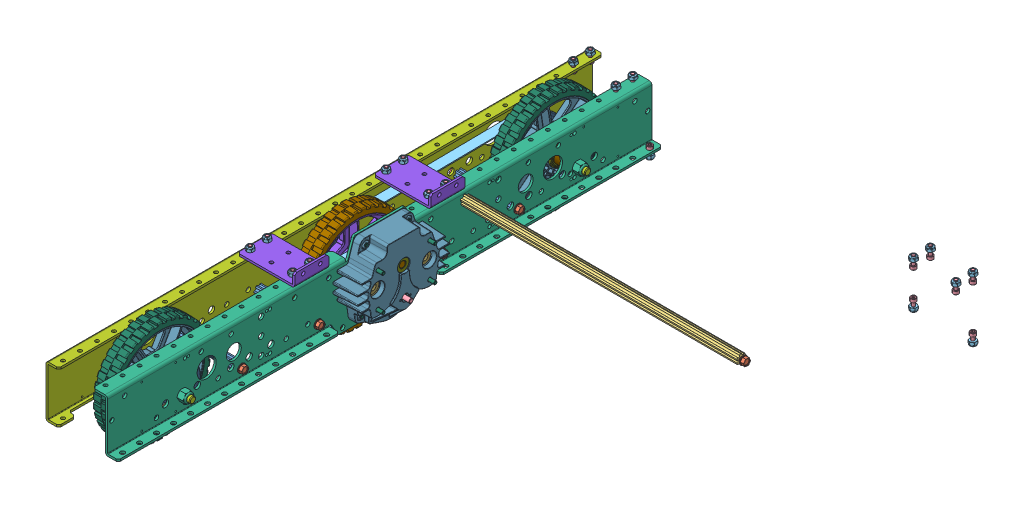
SolidWorks assembly AM14U3Long_Half, configuration Default. Lengths in mm.
Overall size (596.72 219.18 816.74).
153 component instances, 36 part files, 6 mates.
Components (placement in the parent):
- AM14U3Long_Frame_Half-1: AM14U3Long_Frame_Half [Default] at (0 136.144 -762.762) size (595.34 116.33 812.8)
  - 500Churro_3.375-1: 500Churro_3.375 [Default] at (-501.65 -66.929 448.437) x (0 0 1) z (-1 0 0) size (14.66 12.7 85.72)
  - 500Churro_3.375-2: 500Churro_3.375 [Default] at (-501.65 -66.929 562.737) x (0 0 1) z (-1 0 0) size (14.66 12.7 85.72)
  - 500Churro_3.375-3: 500Churro_3.375 [Default] at (-501.65 -66.929 264.287) x (0 0 1) z (-1 0 0) size (14.66 12.7 85.72)
  - 500Churro_3.375-4: 500Churro_3.375 [Default] at (-501.65 -66.929 149.987) x (0 0 1) z (-1 0 0) size (14.66 12.7 85.72)
  - ThreadRollingScrew_0.25-20x0.75_FHTS 0.25-20-G-0.75-C-1: ThreadRollingScrew_0.25-20x0.75_FHTS 0.25-20-G-0.75-C [Default] at (-498.475 -66.929 562.737) x (-1 0 0) z (0 0.924225 0.381849) size (24.64 12.19 12.19)
  - ThreadRollingScrew_0.25-20x0.75_FHTS 0.25-20-G-0.75-C-2: ThreadRollingScrew_0.25-20x0.75_FHTS 0.25-20-G-0.75-C [Default] at (-498.475 -66.929 448.437) x (-1 0 0) z (0 0.924225 0.381849) size (24.64 12.19 12.19)
  - ThreadRollingScrew_0.25-20x0.75_FHTS 0.25-20-G-0.75-C-3: ThreadRollingScrew_0.25-20x0.75_FHTS 0.25-20-G-0.75-C [Default] at (-498.475 -66.929 264.287) x (-1 0 0) z (0 0.924225 0.381849) size (24.64 12.19 12.19)
  - ThreadRollingScrew_0.25-20x0.75_FHTS 0.25-20-G-0.75-C-4: ThreadRollingScrew_0.25-20x0.75_FHTS 0.25-20-G-0.75-C [Default] at (-498.475 -66.929 149.987) x (-1 0 0) z (0 0.924225 0.381849) size (24.64 12.19 12.19)
  - ThreadRollingScrew_0.25-20x0.75_FHTS 0.25-20-G-0.75-C-5: ThreadRollingScrew_0.25-20x0.75_FHTS 0.25-20-G-0.75-C [Default] at (-590.55 -66.929 562.737) size (24.64 12.19 12.19)
  - ThreadRollingScrew_0.25-20x0.75_FHTS 0.25-20-G-0.75-C-6: ThreadRollingScrew_0.25-20x0.75_FHTS 0.25-20-G-0.75-C [Default] at (-590.55 -66.929 448.437) size (24.64 12.19 12.19)
  - ThreadRollingScrew_0.25-20x0.75_FHTS 0.25-20-G-0.75-C-7: ThreadRollingScrew_0.25-20x0.75_FHTS 0.25-20-G-0.75-C [Default] at (-590.55 -66.929 149.987) size (24.64 12.19 12.19)
  - ThreadRollingScrew_0.25-20x0.75_FHTS 0.25-20-G-0.75-C-8: ThreadRollingScrew_0.25-20x0.75_FHTS 0.25-20-G-0.75-C [Default] at (-590.55 -66.929 264.287) size (24.64 12.19 12.19)
  - ThreadRollingScrew_0.25-20x0.75_FHTS 0.25-20-G-0.75-C-9: ThreadRollingScrew_0.25-20x0.75_FHTS 0.25-20-G-0.75-C [Default] at (-501.65 -15.494 229.362) size (24.64 12.19 12.19)
  - ThreadRollingScrew_0.25-20x0.75_FHTS 0.25-20-G-0.75-C-10: ThreadRollingScrew_0.25-20x0.75_FHTS 0.25-20-G-0.75-C [Default] at (-82.55 -15.494 229.362) x (-1 0 0) z (0 -0.924225 -0.381849) size (24.64 12.19 12.19)
  - 500Churro_cut_16.25-1: 500Churro_cut_16.25 [Default] at (-85.725 -15.494 229.362) x (0 0.99241 0.122972) z (-1 0 0) size (14.66 12.7 412.75)
  - Screw_SHCS_10-32x0.5_HX-SHCS 0.19-32x1.375x1-C-1: Screw_SHCS_10-32x0.5_HX-SHCS 0.19-32x1.375x1-C [Default] at (-577.85 -11.43 -11.938) x (0 1 0) z (0 0 1) size (17.53 7.94 7.94)
  - Screw_SHCS_10-32x0.5_HX-SHCS 0.19-32x1.375x1-C-2: Screw_SHCS_10-32x0.5_HX-SHCS 0.19-32x1.375x1-C [Default] at (-577.85 -11.43 -37.338) x (0 1 0) z (0 0 1) size (17.53 7.94 7.94)
  - Screw_SHCS_10-32x0.5_HX-SHCS 0.19-32x1.375x1-C-3: Screw_SHCS_10-32x0.5_HX-SHCS 0.19-32x1.375x1-C [Default] at (-514.35 -11.43 -37.338) x (0 1 0) z (0 0 1) size (17.53 7.94 7.94)
  - Screw_SHCS_10-32x0.5_HX-SHCS 0.19-32x1.375x1-C-4: Screw_SHCS_10-32x0.5_HX-SHCS 0.19-32x1.375x1-C [Default] at (-514.35 -11.43 -11.938) x (0 1 0) z (0 0 1) size (17.53 7.94 7.94)
  - Screw_SHCS_10-32x0.5_HX-SHCS 0.19-32x1.375x1-C-5: Screw_SHCS_10-32x0.5_HX-SHCS 0.19-32x1.375x1-C [Default] at (-488.95 -73.152 -37.338) x (0 -1 0) z (0 0 1) size (17.53 7.94 7.94)
  - Screw_SHCS_10-32x0.5_HX-SHCS 0.19-32x1.375x1-C-6: Screw_SHCS_10-32x0.5_HX-SHCS 0.19-32x1.375x1-C [Default] at (-577.85 -73.152 -37.338) x (0 -1 0) z (0 0 1) size (17.53 7.94 7.94)
  - Screw_SHCS_10-32x0.5_HX-SHCS 0.19-32x1.375x1-C-7: Screw_SHCS_10-32x0.5_HX-SHCS 0.19-32x1.375x1-C [Default] at (-6.35 -11.176 -11.938) x (0 1 0) z (-0.991845 0 0.127447) size (17.53 7.94 7.94)
  - Screw_SHCS_10-32x0.5_HX-SHCS 0.19-32x1.375x1-C-8: Screw_SHCS_10-32x0.5_HX-SHCS 0.19-32x1.375x1-C [Default] at (-6.35 -11.176 -37.338) x (0 1 0) z (0.595464 0 0.803382) size (17.53 7.94 7.94)
  - Screw_SHCS_10-32x0.5_HX-SHCS 0.19-32x1.375x1-C-9: Screw_SHCS_10-32x0.5_HX-SHCS 0.19-32x1.375x1-C [Default] at (-69.85 -11.176 -11.938) x (0 1 0) z (0.578861 0 0.815426) size (17.53 7.94 7.94)
  - Screw_SHCS_10-32x0.5_HX-SHCS 0.19-32x1.375x1-C-10: Screw_SHCS_10-32x0.5_HX-SHCS 0.19-32x1.375x1-C [Default] at (-69.85 -11.176 -37.338) x (0 1 0) z (0.958905 0 0.283727) size (17.53 7.94 7.94)
  - Screw_SHCS_10-32x0.5_HX-SHCS 0.19-32x1.375x1-C-11: Screw_SHCS_10-32x0.5_HX-SHCS 0.19-32x1.375x1-C [Default] at (-6.35 -73.406 -37.338) x (0 -1 0) z (-0.989362 0 -0.145473) size (17.53 7.94 7.94)
  - Screw_SHCS_10-32x0.5_HX-SHCS 0.19-32x1.375x1-C-12: Screw_SHCS_10-32x0.5_HX-SHCS 0.19-32x1.375x1-C [Default] at (-95.25 -73.406 -37.338) x (0 -1 0) z (-0.875347 0 0.483496) size (17.53 7.94 7.94)
  - NylockNut_10-32-1: NylockNut_10-32 [Default] at (-69.85 0 -11.938) x (1 0 0) z (0 1 0) size (9.53 11 5.96)
  - NylockNut_10-32-2: NylockNut_10-32 [Default] at (-69.85 0 -37.338) x (1 0 0) z (0 1 0) size (9.53 11 5.96)
  - NylockNut_10-32-3: NylockNut_10-32 [Default] at (-6.35 0 -37.338) x (1 0 0) z (0 1 0) size (9.53 11 5.96)
  - NylockNut_10-32-4: NylockNut_10-32 [Default] at (-6.35 0 -11.938) x (1 0 0) z (0 1 0) size (9.53 11 5.96)
  - NylockNut_10-32-5: NylockNut_10-32 [Default] at (-6.35 -84.582 -37.338) x (1 0 0) z (0 -1 0) size (9.53 11 5.96)
  - NylockNut_10-32-6: NylockNut_10-32 [Default] at (-95.25 -84.582 -37.338) x (1 0 0) z (0 -1 0) size (9.53 11 5.96)
  - NylockNut_10-32-7: NylockNut_10-32 [Default] at (-514.35 0 -11.938) x (1 0 0) z (0 1 0) size (9.53 11 5.96)
  - NylockNut_10-32-8: NylockNut_10-32 [Default] at (-514.35 0 -37.338) x (1 0 0) z (0 1 0) size (9.53 11 5.96)
  - NylockNut_10-32-9: NylockNut_10-32 [Default] at (-577.85 0 -37.338) x (1 0 0) z (0 1 0) size (9.53 11 5.96)
  - NylockNut_10-32-10: NylockNut_10-32 [Default] at (-577.85 0 -11.938) x (1 0 0) z (0 1 0) size (9.53 11 5.96)
  - NylockNut_10-32-11: NylockNut_10-32 [Default] at (-488.95 -84.582 -37.338) x (1 0 0) z (0 -1 0) size (9.53 11 5.96)
  - NylockNut_10-32-12: NylockNut_10-32 [Default] at (-577.85 -84.582 -37.338) x (1 0 0) z (0 -1 0) size (9.53 11 5.96)
  - Screw_SHCS_10-32x0.5_HX-SHCS 0.19-32x1.375x1-C-13: Screw_SHCS_10-32x0.5_HX-SHCS 0.19-32x1.375x1-C [Default] at (-577.85 -11.43 445.262) x (0 1 0) z (0 0 1) size (17.53 7.94 7.94)
  - Screw_SHCS_10-32x0.5_HX-SHCS 0.19-32x1.375x1-C-14: Screw_SHCS_10-32x0.5_HX-SHCS 0.19-32x1.375x1-C [Default] at (-577.85 -11.43 470.662) x (0 1 0) z (0 0 1) size (17.53 7.94 7.94)
  - Screw_SHCS_10-32x0.5_HX-SHCS 0.19-32x1.375x1-C-15: Screw_SHCS_10-32x0.5_HX-SHCS 0.19-32x1.375x1-C [Default] at (-514.35 -11.43 445.262) x (0 1 0) z (0 0 1) size (17.53 7.94 7.94)
  - Screw_SHCS_10-32x0.5_HX-SHCS 0.19-32x1.375x1-C-16: Screw_SHCS_10-32x0.5_HX-SHCS 0.19-32x1.375x1-C [Default] at (-514.35 -11.43 470.662) x (0 1 0) z (0 0 1) size (17.53 7.94 7.94)
  - Screw_SHCS_10-32x0.5_HX-SHCS 0.19-32x1.375x1-C-17: Screw_SHCS_10-32x0.5_HX-SHCS 0.19-32x1.375x1-C [Default] at (-577.85 -11.43 267.462) x (0 1 0) z (0 0 1) size (17.53 7.94 7.94)
  - Screw_SHCS_10-32x0.5_HX-SHCS 0.19-32x1.375x1-C-18: Screw_SHCS_10-32x0.5_HX-SHCS 0.19-32x1.375x1-C [Default] at (-577.85 -11.43 242.062) x (0 1 0) z (0 0 1) size (17.53 7.94 7.94)
  - Screw_SHCS_10-32x0.5_HX-SHCS 0.19-32x1.375x1-C-19: Screw_SHCS_10-32x0.5_HX-SHCS 0.19-32x1.375x1-C [Default] at (-514.35 -11.43 242.062) x (0 1 0) z (0 0 1) size (17.53 7.94 7.94)
  - Screw_SHCS_10-32x0.5_HX-SHCS 0.19-32x1.375x1-C-20: Screw_SHCS_10-32x0.5_HX-SHCS 0.19-32x1.375x1-C [Default] at (-514.35 -11.43 267.462) x (0 1 0) z (0 0 1) size (17.53 7.94 7.94)
  - NylockNut_10-32-13: NylockNut_10-32 [Default] at (-514.35 -0.254 267.462) x (1 0 0) z (0 1 0) size (9.53 11 5.96)
  - NylockNut_10-32-14: NylockNut_10-32 [Default] at (-514.35 -0.254 242.062) x (1 0 0) z (0 1 0) size (9.53 11 5.96)
  - NylockNut_10-32-15: NylockNut_10-32 [Default] at (-577.85 -0.254 267.462) x (1 0 0) z (0 1 0) size (9.53 11 5.96)
  - NylockNut_10-32-16: NylockNut_10-32 [Default] at (-577.85 -0.254 242.062) x (1 0 0) z (0 1 0) size (9.53 11 5.96)
  - NylockNut_10-32-17: NylockNut_10-32 [Default] at (-514.35 -0.254 470.662) x (1 0 0) z (0 1 0) size (9.53 11 5.96)
  - NylockNut_10-32-18: NylockNut_10-32 [Default] at (-577.85 -0.254 470.662) x (1 0 0) z (0 1 0) size (9.53 11 5.96)
  - NylockNut_10-32-19: NylockNut_10-32 [Default] at (-577.85 -0.254 445.262) x (1 0 0) z (0 1 0) size (9.53 11 5.96)
  - NylockNut_10-32-20: NylockNut_10-32 [Default] at (-514.35 -0.254 445.262) x (1 0 0) z (0 1 0) size (9.53 11 5.96)
  - AM14U3InnerPlate_Long-1: AM14U3InnerPlate_Long [Default] at (-501.65 -77.216 762.762) x (0 0 -1) z (0 -1 0) size (812.8 38.1 116.33)
  - AM14U3OuterPlate_Long_DefaultSM-FLAT-PATTERN-1: AM14U3OuterPlate_Long_DefaultSM-FLAT-PATTERN [Default] at (-587.375 -77.216 -50.038) x (0 0 1) z (0 -1 0) size (812.8 19.05 77.72)
  - Bracket_2x3-1: Bracket_2x3 [Default] at (-584.2 -3.429 496.062) size (85.72 19.05 50.8)
  - Bracket_2x3-2: Bracket_2x3 [Default] at (-584.2 -3.429 292.862) size (85.72 19.05 50.8)
- ToughboxMini-1: ToughboxMini [Default] at (-549.0167 66.1299 -315.2992) x (0 0.001296 0.999999) z (-1 0 0) size (140.05 131.62 142.29)
  - TBMiniSmallHexShaft-1: TBMiniSmallHexShaft [Default] at (-127.8104 29.3671 -52.3959) x (-0.59657 -0.802561 0) z (-0.802561 0.59657 0) size (11 38.23 9.52)
  - ToughboxLargeClusterGear_Hex_50t0.375-1: ToughboxLargeClusterGear_Hex_50t0.375 [Default] at (-91.0349 50.9043 -67.5597) x (-0.59657 -0.802561 0) z (0 0 -1) size (65.97 66.04 10.34)
  - Bearing_FR6ZZ-1: Bearing_FR6ZZ [Default] at (-96.247 60.278 -52.5991) x (-0.893862 0.448342 0) z (0 0 1) size (24.69 24.69 7.16)
  - NylockNut_10-32-1: NylockNut_10-32 [Default] at (-129.8464 -8.0737 -56.3837) x (0.501678 0.865055 0) z (0 0 -1) size (9.53 11 5.96)
  - NylockNut_10-32-2: NylockNut_10-32 [Default] at (-59.2462 80.7349 -56.3837) x (0.999999 -0.001296 0) z (0 0 -1) size (9.53 11 5.96)
  - NylockNut_10-32-3: NylockNut_10-32 [Default] at (-122.7461 80.8172 -56.3837) x (0.500567 0.865698 0) z (0 0 -1) size (9.53 11 5.96)
  - NylockNut_10-32-4: NylockNut_10-32 [Default] at (-52.3764 -8.1741 -56.3837) x (-0.501678 -0.865055 0) z (0 0 -1) size (9.53 11 5.96)
  - Washer_5-16-1: Washer_5-16 [Default] at (-52.3162 38.3079 -77.7705) x (0.171117 0.985251 0) z (0 0 -1) size (17.53 17.53 1.47)
  - Washer_5-16-2: Washer_5-16 [Default] at (-52.3162 38.3079 -76.2973) x (0.897267 -0.441488 0) z (0 0 -1) size (17.53 17.53 1.47)
  - Washer_5-16-3: Washer_5-16 [Default] at (-129.7861 38.4083 -77.7705) x (-0.990116 0.140253 0) z (0 0 1) size (17.53 17.53 1.47)
  - Washer_5-16-4: Washer_5-16 [Default] at (-129.7861 38.4083 -79.2437) x (-0.681761 0.731575 0) z (0 0 1) size (17.53 17.53 1.47)
  - CIMGear_14t8mm-1: CIMGear_14t8mm [Default] at (-52.3162 38.3079 -63.5973) x (-0.998626 0.052407 0) z (0 0 -1) size (20.03 20.32 12.7)
  - CIMGear_14t8mm-2: CIMGear_14t8mm [Default] at (-129.7861 38.4083 -63.5973) x (-0.70887 0.705339 0) z (0 0 -1) size (20.03 20.32 12.7)
  - TBMiniHousing-1: TBMiniHousing [Default] at (-91.0876 10.1882 -86.3557) x (0.999999 -0.001296 0) z (0 0 1) size (139.9 118.55 41.62)
  - Screw_SHCS_10-32x0.625-1: Screw_SHCS_10-32x0.625 [Default] at (-52.2832 63.7078 -74.4685) x (-0.564778 -0.825243 0) z (-0.825243 0.564778 0) size (7.82 20.65 7.82)
  - Screw_SHCS_10-32x0.625-2: Screw_SHCS_10-32x0.625 [Default] at (-122.7461 80.8172 -42.5915) x (0.507484 -0.861661 0) z (-0.861661 -0.507484 0) size (7.82 20.65 7.82)
  - Screw_SHCS_10-32x0.625-3: Screw_SHCS_10-32x0.625 [Default] at (-52.3764 -8.1741 -42.5915) x (0.507484 -0.861661 0) z (-0.861661 -0.507484 0) size (7.82 20.65 7.82)
  - Screw_SHCS_10-32x0.625-4: Screw_SHCS_10-32x0.625 [Default] at (-129.8464 -8.0737 -42.5915) x (0.507484 -0.861661 0) z (-0.861661 -0.507484 0) size (7.82 20.65 7.82)
  - Screw_SHCS_10-32x0.625-5: Screw_SHCS_10-32x0.625 [Default] at (-59.2462 80.7349 -42.5915) x (0.740711 -0.671824 0) z (-0.671824 -0.740711 0) size (7.82 20.65 7.82)
  - Screw_SHCS_10-32x0.625-6: Screw_SHCS_10-32x0.625 [Default] at (-52.3491 12.9079 -74.4685) x (-0.564778 -0.825243 0) z (-0.825243 0.564778 0) size (7.82 20.65 7.82)
  - Screw_SHCS_10-32x0.625-7: Screw_SHCS_10-32x0.625 [Default] at (-129.7532 63.8083 -74.4685) x (-0.966277 -0.257503 0) z (-0.257503 0.966277 0) size (7.82 20.65 7.82)
  - Screw_SHCS_10-32x0.625-8: Screw_SHCS_10-32x0.625 [Default] at (-129.819 13.0083 -74.4685) x (-0.99652 0.083357 0) z (0.083357 0.99652 0) size (7.82 20.65 7.82)
  - Bearing_R6ZZ-1: Bearing_R6ZZ [Default] at (-91.0349 50.9043 -84.8317) x (0.958138 -0.286306 0) z (0 0 1) size (22.23 22.23 7.11)
  - Bearing_R6ZZ-2: Bearing_R6ZZ [Default] at (-91.0876 10.1882 -84.8317) x (-0.661529 0.74992 0) z (0 0 1) size (22.23 22.23 7.11)
  - RetainingClip-1: RetainingClip [Default] at (-129.7861 38.4083 -63.5973) x (0 0 1) z (-1 0 0) size (1.12 14.83 14.83)
  - RetainingClip-2: RetainingClip [Default] at (-52.3162 38.3079 -63.5973) x (0 0 1) z (-1 0 0) size (1.12 14.83 14.83)
  - ExternalKlipring-1: ExternalKlipring [Default] at (-91.0876 10.1882 -64.4355) x (0.996411 -0.084651 0) z (0 0 1) size (19.07 20.96 1.27)
  - Bearing_Hex_FR8ZZ-1: Bearing_Hex_FR8ZZ [Default] at (-91.0876 10.1882 -44.6717) x (0.188693 -0.982036 0) z (0 0 -1) size (31.12 31.12 7.93)
  - SmallClusterGear_Hex_16t0.375-1: SmallClusterGear_Hex_16t0.375 [Default] at (-91.0349 50.9043 -67.5597) x (0 0 1) z (0.396753 -0.917925 0) size (15.19 22.57 22.57)
  - LargeOutputGear_Hex_48t0.5-1: LargeOutputGear_Hex_48t0.5 [Default] at (-91.0876 10.1882 -63.1655) x (0 0 1) z (0.756122 0.654431 0) size (10.21 63.42 63.42)
  - TBMiniHexOutputShaft-1: TBMiniHexOutputShaft [Default] at (-100.2289 -30.5762 -52.3197) x (0.188693 -0.982036 0) z (-0.982036 -0.188693 0) size (14.66 142.29 12.7)
- Bearing_Hex_FR8ZZ-1: Bearing_Hex_FR8ZZ [Default] at (-593.7783 76.2 -406.4) x (0 0.32638 -0.945239) z (1 0 0) size (31.12 31.12 7.93)
- Belt_15mm_Long-1: Belt_15mm_Long [Default] at (-511.5261 79.756 -111.3496) x (0 -0.012051 -0.999927) z (0 0.999927 -0.012051) size (368.15 15 73.08)
- Belt_15mm_Long-2: Belt_15mm_Long [Default] at (-576.9127 76.2 -406.4) x (0 0.012051 -0.999927) z (0 -0.999927 -0.012051) size (368.15 15 73.08)
- NylockNut_0.375-16_91831A127-1: NylockNut_0.375-16_91831A127 [Default] at (-498.475 79.756 -701.4504) x (0 -1 0) z (0 0 1) size (14.29 12 16.5)
- NylockNut_0.375-16_91831A127-2: NylockNut_0.375-16_91831A127 [Default] at (-498.475 79.7563 -111.3496) x (0 -1 0) z (0 0 1) size (14.29 12 16.5)
- HHSBolt_0.375-16x4.25_HFBOLT 0.375-16x2.5x1-C-1: HHSBolt_0.375-16x4.25_HFBOLT 0.375-16x2.5x1-C [Default] at (-596.7222 79.756 -111.3496) size (114.12 16.48 14.27)
- HHSBolt_0.375-16x4.25_HFBOLT 0.375-16x2.5x1-C-2: HHSBolt_0.375-16x4.25_HFBOLT 0.375-16x2.5x1-C [Default] at (-596.7222 79.756 -701.4504) x (1 0 0) z (0 -0.203423 -0.979091) size (114.12 16.48 14.27)
- Wheel_6inHiGrip_Center-1: Wheel_6inHiGrip_Center [Default] at (-513.0653 208.3565 -483.6317) x (-1 0 0) z (0 -0.493281 0.86987) size (81.42 191.55 191.55)
  - Wheel_6inHiGrip-1: Wheel_6inHiGrip [Default] at (83.7987 67.439 110.9939) size (34.93 191.55 191.55)
    - Wheel_6inHiGrip_Wheel-1: Wheel_6inHiGrip_Wheel [Default] at (-52.6446 9.4231 21.378) size (34.93 132.08 132.08)
    - Wheel_6inHiGrip_Tread-1: Wheel_6inHiGrip_Tread [Default] at (-65.3446 9.4231 21.378) x (0 -0.304368 -0.952555) z (1 0 0) size (152.4 152.4 25.58)
  - HalfPulley_42t5mm-1: HalfPulley_42t5mm [Default] at (47.6006 76.862 132.3719) x (1 0 0) z (0 -0.5 0.866025) size (13 74.23 74.23)
  - HalfPulley_42t5mm-2: HalfPulley_42t5mm [Default] at (64.263 76.862 132.3719) x (-1 0 0) z (0 -0.499927 0.866067) size (13 74.23 74.23)
  - ThreadFormingScrew_10-24x1.25_93882A213-1: ThreadFormingScrew_10-24x1.25_93882A213 [Default] at (63.247 76.8605 108.5602) x (0 0.953802 -0.300437) z (1 0 0) size (10.52 10.52 35.59)
  - ThreadFormingScrew_10-24x1.25_93882A213-2: ThreadFormingScrew_10-24x1.25_93882A213 [Default] at (63.247 97.4833 120.4656) x (0 0.953802 -0.300437) z (1 0 0) size (10.52 10.52 35.59)
  - ThreadFormingScrew_10-24x1.25_93882A213-3: ThreadFormingScrew_10-24x1.25_93882A213 [Default] at (63.247 56.2398 144.2799) x (0 0.953802 -0.300437) z (1 0 0) size (10.52 10.52 35.59)
  - ThreadFormingScrew_10-24x1.25_93882A213-4: ThreadFormingScrew_10-24x1.25_93882A213 [Default] at (63.247 76.8625 156.1852) x (0 -0.013882 -0.999904) z (1 0 0) size (10.52 10.52 35.59)
  - ThreadFormingScrew_10-24x1.25_93882A213-5: ThreadFormingScrew_10-24x1.25_93882A213 [Default] at (63.247 97.4843 144.2781) x (0 -0.733065 -0.680158) z (1 0 0) size (10.52 10.52 35.59)
  - ThreadFormingScrew_10-24x1.25_93882A213-6: ThreadFormingScrew_10-24x1.25_93882A213 [Default] at (63.247 56.2388 120.4674) x (0 0.407306 -0.913292) z (1 0 0) size (10.52 10.52 35.59)
  - HalfPulley_42t5mm-3: HalfPulley_42t5mm [Default] at (-1.9548 76.862 132.3719) x (1 0 0) z (0 -1 -0.000063) size (13 74.23 74.23)
  - HalfPulley_42t5mm-4: HalfPulley_42t5mm [Default] at (14.7076 76.862 132.3719) x (-1 0 0) z (0 -1 0.000021) size (13 74.23 74.23)
  - HexHub_500EX-1: HexHub_500EX [Default] at (-8.3048 76.862 132.3719) x (0 -0.866025 -0.5) z (0 -0.5 0.866025) size (55.37 25.4 51.33)
  - ThreadFormingScrew_10-24x1.25_93882A213-7: ThreadFormingScrew_10-24x1.25_93882A213 [Default] at (-5.2568 97.4843 120.4656) x (0 -0.953802 0.300437) z (-1 0 0) size (10.52 10.52 35.59)
  - ThreadFormingScrew_10-24x1.25_93882A213-8: ThreadFormingScrew_10-24x1.25_93882A213 [Default] at (-5.2568 76.862 108.5594) x (0 -0.953802 0.300437) z (-1 0 0) size (10.52 10.52 35.59)
  - ThreadFormingScrew_10-24x1.25_93882A213-9: ThreadFormingScrew_10-24x1.25_93882A213 [Default] at (-5.2568 56.2398 120.4656) x (0 -0.953802 0.300437) z (-1 0 0) size (10.52 10.52 35.59)
  - ThreadFormingScrew_10-24x1.25_93882A213-10: ThreadFormingScrew_10-24x1.25_93882A213 [Default] at (-5.2568 97.4843 144.2781) x (0 -0.192002 -0.981394) z (-1 0 0) size (10.52 10.52 35.59)
  - ThreadFormingScrew_10-24x1.25_93882A213-11: ThreadFormingScrew_10-24x1.25_93882A213 [Default] at (-5.2568 56.2398 144.2781) x (0 -0.986288 0.16503) z (-1 0 0) size (10.52 10.52 35.59)
  - ThreadFormingScrew_10-24x1.25_93882A213-12: ThreadFormingScrew_10-24x1.25_93882A213 [Default] at (-5.2568 76.862 156.1844) x (0 -0.150217 -0.988653) z (-1 0 0) size (10.52 10.52 35.59)
  - Spacer_Hex_0.57x0.5-1: Spacer_Hex_0.57x0.5 [Default] at (57.8495 76.862 132.3719) x (0 -0.866025 -0.5) z (0 -0.5 0.866025) size (28.55 14.48 28.55)
- 6 HiGrip with bearings, pulleys and spacers-1: 6 HiGrip with bearings, pulleys and spacers [Default] at (-574.9579 3.6159 21.4388) x (1 0 0) z (0 0.865776 -0.500432) size (85.56 152.4 152.4)
  - 6 HiGrip Wheel Assembly Rev II-1: 6 HiGrip Wheel Assembly Rev II [Default] at (83.7987 67.439 110.9939) size (34.93 152.4 152.4)
    - 6 wheel Rev 4-1: 6 wheel Rev 4 [Default] at (-52.6446 9.4231 21.378) size (34.93 132.08 132.08)
    - 6 wheel tread II-1: 6 wheel tread II [Default] at (-65.3446 9.4231 21.378) x (0 0 -1) z (1 0 0) size (152.4 152.4 25.58)
  - HalfPulley_42t5mm-1: HalfPulley_42t5mm [Default] at (47.6006 76.862 132.3719) x (1 0 0) z (0 -0.5 0.866025) size (13 74.23 74.23)
  - HalfPulley_42t5mm-2: HalfPulley_42t5mm [Default] at (64.263 76.862 132.3719) x (-1 0 0) z (0 -0.499927 0.866067) size (13 74.23 74.23)
  - Bearing_1614ZZ-1: Bearing_1614ZZ [Default] at (62.612 76.862 132.3719) x (0 0.904908 -0.425608) z (-1 0 0) size (28.58 28.58 9.53)
  - Bearing_1614ZZ-2: Bearing_1614ZZ [Default] at (15.2791 76.862 132.3719) x (0 0.960548 -0.278115) z (1 0 0) size (28.58 28.58 9.53)
  - Washer_5-16-1: Washer_5-16 [Default] at (63.247 76.8605 108.5602) x (0 -0.624545 -0.780988) z (1 0 0) size (17.53 17.53 1.47)
  - Washer_5-16-2: Washer_5-16 [Default] at (63.247 97.4833 120.4656) x (0 -0.995817 0.091369) z (1 0 0) size (17.53 17.53 1.47)
  - Washer_5-16-3: Washer_5-16 [Default] at (63.247 56.2398 144.2799) x (0 0.546149 0.837688) z (1 0 0) size (17.53 17.53 1.47)
  - Washer_5-16-4: Washer_5-16 [Default] at (63.247 76.8625 156.1852) x (0 0.642695 -0.766122) z (1 0 0) size (17.53 17.53 1.47)
  - Washer_5-16-5: Washer_5-16 [Default] at (63.247 97.4843 144.2781) x (0 0.936259 -0.351311) z (1 0 0) size (17.53 17.53 1.47)
  - Washer_5-16-6: Washer_5-16 [Default] at (63.247 56.2388 120.4674) x (0 -0.160557 -0.987027) z (1 0 0) size (17.53 17.53 1.47)
  - Spacer_0.28x0.382-1: Spacer_0.28x0.382 [Default] at (74.4865 76.862 132.3719) x (0 -0.996837 -0.07947) z (-1 0 0) size (13.16 13.16 7.11)
  - Spacer_0.85x0.38-1: Spacer_0.85x0.38 [Default] at (-11.0734 76.862 132.3719) x (0 0.960548 -0.278115) z (1 0 0) size (19.05 19.05 21.59)
- 6 HiGrip with bearings, pulleys and spacers-2: 6 HiGrip with bearings, pulleys and spacers [Default] at (-513.4809 -62.9554 -646.1011) x (-1 0 0) z (0 0.624698 -0.780867) size (85.56 152.4 152.4)
  - 6 HiGrip Wheel Assembly Rev II-1: 6 HiGrip Wheel Assembly Rev II [Default] at (83.7987 67.439 110.9939) size (34.93 152.4 152.4)
    - 6 wheel Rev 4-1: 6 wheel Rev 4 [Default] at (-52.6446 9.4231 21.378) size (34.93 132.08 132.08)
    - 6 wheel tread II-1: 6 wheel tread II [Default] at (-65.3446 9.4231 21.378) x (0 0 -1) z (1 0 0) size (152.4 152.4 25.58)
  - HalfPulley_42t5mm-1: HalfPulley_42t5mm [Default] at (47.6006 76.862 132.3719) x (1 0 0) z (0 -0.5 0.866025) size (13 74.23 74.23)
  - HalfPulley_42t5mm-2: HalfPulley_42t5mm [Default] at (64.263 76.862 132.3719) x (-1 0 0) z (0 -0.499927 0.866067) size (13 74.23 74.23)
  - Bearing_1614ZZ-1: Bearing_1614ZZ [Default] at (62.612 76.862 132.3719) x (0 0.904908 -0.425608) z (-1 0 0) size (28.58 28.58 9.53)
  - Bearing_1614ZZ-2: Bearing_1614ZZ [Default] at (15.2791 76.862 132.3719) x (0 0.960548 -0.278115) z (1 0 0) size (28.58 28.58 9.53)
  - Washer_5-16-1: Washer_5-16 [Default] at (63.247 76.8605 108.5602) x (0 -0.624545 -0.780988) z (1 0 0) size (17.53 17.53 1.47)
  - Washer_5-16-2: Washer_5-16 [Default] at (63.247 97.4833 120.4656) x (0 -0.995817 0.091369) z (1 0 0) size (17.53 17.53 1.47)
  - Washer_5-16-3: Washer_5-16 [Default] at (63.247 56.2398 144.2799) x (0 0.546149 0.837688) z (1 0 0) size (17.53 17.53 1.47)
  - Washer_5-16-4: Washer_5-16 [Default] at (63.247 76.8625 156.1852) x (0 0.642695 -0.766122) z (1 0 0) size (17.53 17.53 1.47)
  - Washer_5-16-5: Washer_5-16 [Default] at (63.247 97.4843 144.2781) x (0 0.936259 -0.351311) z (1 0 0) size (17.53 17.53 1.47)
  - Washer_5-16-6: Washer_5-16 [Default] at (63.247 56.2388 120.4674) x (0 -0.160557 -0.987027) z (1 0 0) size (17.53 17.53 1.47)
  - Spacer_0.28x0.382-1: Spacer_0.28x0.382 [Default] at (74.4865 76.862 132.3719) x (0 -0.996837 -0.07947) z (-1 0 0) size (13.16 13.16 7.11)
  - Spacer_0.85x0.38-1: Spacer_0.85x0.38 [Default] at (-11.0734 76.862 132.3719) x (0 0.960548 -0.278115) z (1 0 0) size (19.05 19.05 21.59)
Mates (geometry in assembly coordinates):
- Concentric1: concentric anti-aligned: cylinder of HHSBolt_0.375-16x4.25_HFBOLT 0.375-16x2.5x1-C-1 through (-596.7222 79.756 -111.3496) axis (-1 0 0) radius 4.7625; cylinder of 6 HiGrip with bearings, pulleys and spacers-1/Spacer_0.28x0.382-1 through (-507.5834 79.756 -111.3496) axis (1 0 0) radius 4.8514
- Concentric2: concentric anti-aligned: cylinder of HHSBolt_0.375-16x4.25_HFBOLT 0.375-16x2.5x1-C-2 through (-596.7222 79.756 -701.4504) axis (-1 0 0) radius 4.7625; cylinder of 6 HiGrip with bearings, pulleys and spacers-2/Spacer_0.85x0.38-1 through (-523.9975 79.756 -701.4504) axis (1 0 0) radius 4.826
- Coincident1: coincident aligned: axis of Belt_15mm_Long-2 through (-561.9127 76.2 -406.4) axis (-1 0 0); axis of Wheel_6inHiGrip_Center-1/HalfPulley_42t5mm-2 through (-558.4587 76.2 -406.4) axis (-1 0 0)
- Width1: width anti-aligned: plane of Belt_15mm_Long-2 through (-561.9127 76.2 -406.4) normal (1 0 0); plane of Belt_15mm_Long-2 through (-576.9127 76.2 -406.4) normal (-1 0 0); plane of 6 HiGrip with bearings, pulleys and spacers-2/HalfPulley_42t5mm-2 through (-580.2839 47.6626 -706.3412) normal (-1 0 0); plane of 6 HiGrip with bearings, pulleys and spacers-2/HalfPulley_42t5mm-1 through (-558.5415 111.8498 -696.5623) normal (1 0 0)
- Width2: width anti-aligned: plane of Belt_15mm_Long-1 through (-511.5261 79.756 -111.3496) normal (1 0 0); plane of Belt_15mm_Long-2 through (-576.9127 76.2 -406.4) normal (-1 0 0); plane of Wheel_6inHiGrip_Center-1/HalfPulley_42t5mm-2 through (-579.8683 108.663 -406.6486) normal (-1 0 0); plane of Wheel_6inHiGrip_Center-1/HalfPulley_42t5mm-3 through (-508.5705 60.1879 -378.1596) normal (1 0 0)
- Width3: width anti-aligned: plane of Belt_15mm_Long-1 through (-526.5261 79.756 -111.3496) normal (-1 0 0); plane of Belt_15mm_Long-1 through (-511.5261 79.756 -111.3496) normal (1 0 0); plane of 6 HiGrip with bearings, pulleys and spacers-1/HalfPulley_42t5mm-2 through (-508.1549 79.7749 -78.8857) normal (1 0 0); plane of 6 HiGrip with bearings, pulleys and spacers-1/HalfPulley_42t5mm-1 through (-529.8973 79.7398 -143.8135) normal (-1 0 0)
